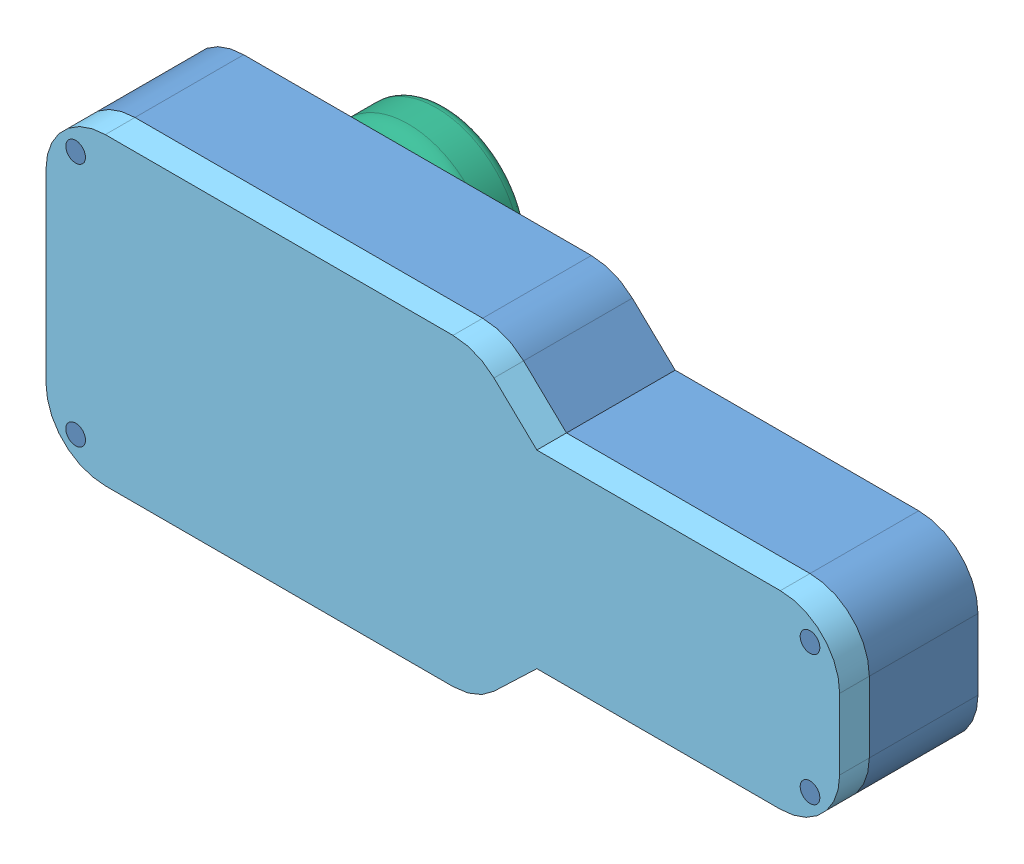
SolidWorks assembly FullModel, configuration Default. Lengths in mm.
Overall size (80.31 30.78 27).
6 component instances, 6 part files, 10 mates.
Components (placement in the parent):
- CaseBottom-1: CaseBottom [Default] at (33.019 -6.2949 -13.147) size (80.31 30.78 14)
- PCB-1: PCB [Default] at (-38.291 -12.1049 -13.147) size (40.02 21.78 3)
- IMU-1: IMU [Default] at (33.019 -6.2949 -10.147) size (34.29 10.16 3)
- Arduino-1: Arduino [Default] at (-3.271 -10.1049 -10.147) size (33.02 17.78 3)
- CaseCover-1: CaseCover [Default] at (33.019 -6.2949 -5.147) size (80.31 30.78 3)
- EarPlug-1: EarPlug [Default] at (-29.2878 -1.2199 -16.147) x (0 0 1) z (-1 0 0) size (13 17 17)
Mates (geometry in assembly coordinates):
- Coincident1: coincident anti-aligned: line of CaseBottom-1 through (-38.291 -12.1049 -13.147) axis (0 1 0); line of PCB-1 through (-38.291 9.6751 -13.147) axis (0 -1 0)
- Coincident2: coincident anti-aligned: line of CaseBottom-1 through (-1.271 -12.1049 -13.147) axis (-1 0 0); line of PCB-1 through (-38.291 -12.1049 -13.147) axis (1 0 0)
- Coincident3: coincident anti-aligned: plane of PCB-1 through (-38.291 -12.1049 -10.147) normal (0 0 1); plane of IMU-1 through (33.019 -6.2949 -10.147) normal (0 0 -1)
- Coincident4: coincident: line of CaseBottom-1 through (-1.271 3.8651 -13.147) axis (0 -1 0); plane of IMU-1 through (-1.271 3.8651 -7.147) normal (-1 0 0)
- Coincident5: coincident: line of CaseBottom-1 through (-1.271 3.8651 -13.147) axis (1 0 0); plane of IMU-1 through (-1.271 3.8651 -7.147) normal (0 1 0)
- Coincident6: coincident anti-aligned: plane of PCB-1 through (-38.291 -12.1049 -10.147) normal (0 0 1); plane of Arduino-1 through (-3.271 -10.1049 -10.147) normal (0 0 -1)
- Coincident7: coincident: line of CaseBottom-1 through (-36.291 7.6751 -13.147) axis (1 0 0); plane of Arduino-1 through (-36.291 7.6751 -7.147) normal (0 1 0)
- Coincident8: coincident: line of CaseBottom-1 through (-3.271 7.6751 -13.147) axis (0 -1 0); plane of Arduino-1 through (-3.271 7.6751 -7.147) normal (1 0 0)
- Coincident9: coincident aligned: circle of CaseBottom-1; circle of CaseCover-1
- Coincident11: coincident anti-aligned: plane of CaseBottom-1 through (-36.791 8.1751 -16.147) normal (0 0 -1); plane of EarPlug-1 through (-29.2878 2.2801 -16.147) normal (0 0 1)
